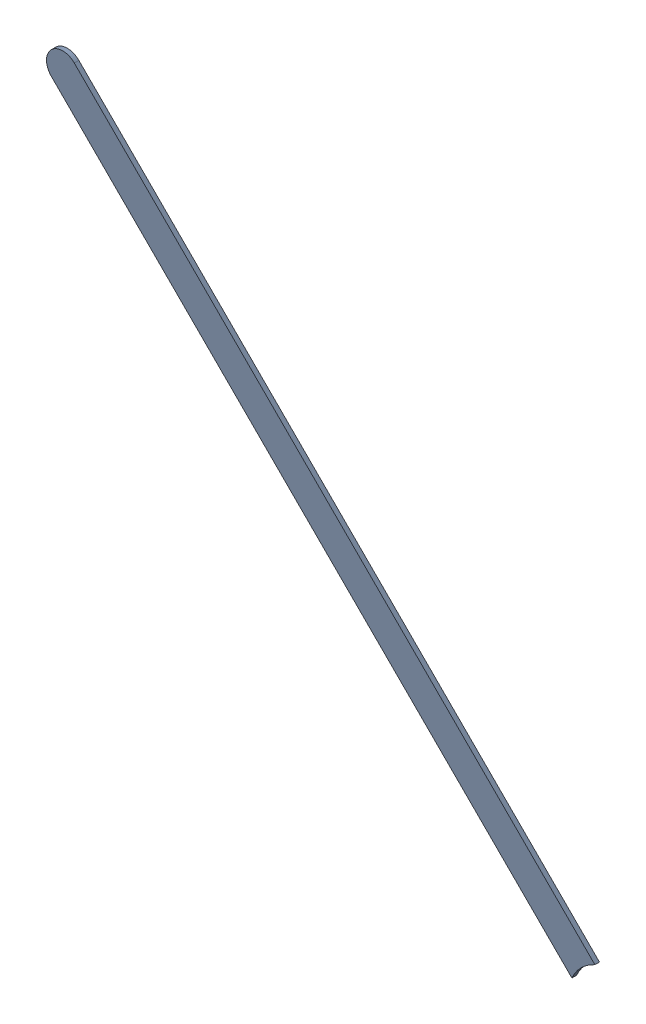
SolidWorks assembly Track (21.9mm,15.3mm)(26.2mm,11mm) on Bottom Layer, configuration Predeterminado. Lengths in mm.
Overall size (4.28 4.28 0.04).
2 component instances, 1 part files, 0 mates.
Components (placement in the parent):
- Track (21.9mm,15.3mm)(26.2mm,11mm) on Bottom Layer-1-1: Track (21.9mm,15.3mm)(26.2mm,11mm) on Bottom Layer-1 [Predeterminado] at (-68.317 -44.187 -0.4013) size (4.28 4.28 0.04)
  - Track (21.9mm,15.3mm)(26.2mm,11mm) on Bottom Layer-Part-1-1: Track (21.9mm,15.3mm)(26.2mm,11mm) on Bottom Layer-Part-1 [Predeterminado] at origin size (4.28 4.28 0.04)
